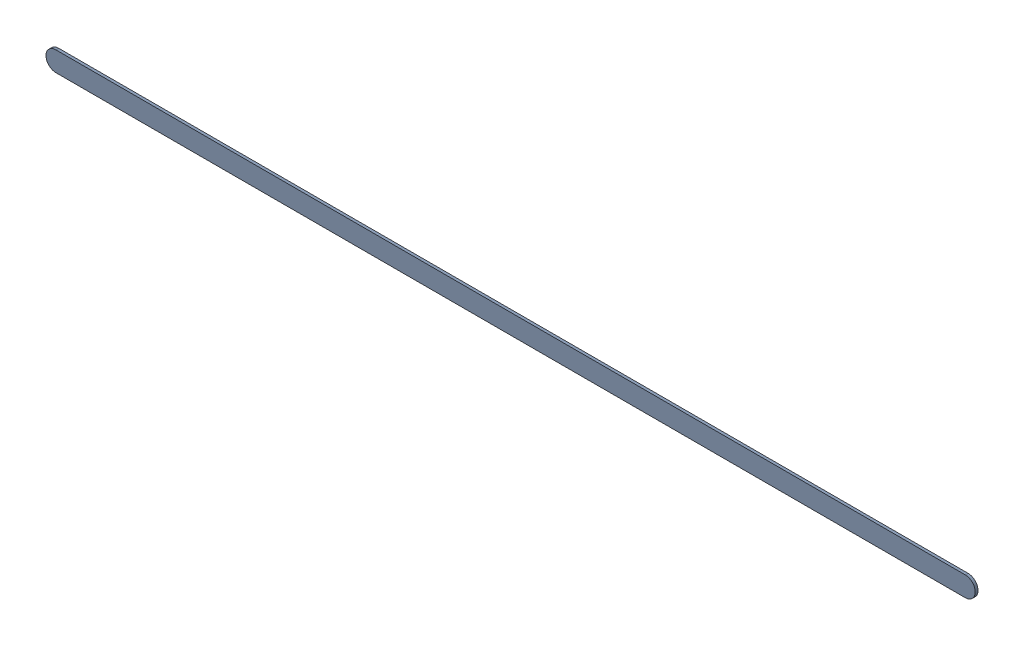
SolidWorks assembly Track (14.5mm,6.8mm)(26.16mm,6.8mm) on Top Layer, configuration Predeterminado. Lengths in mm.
Overall size (11.91 0.25 0.04).
2 component instances, 1 part files, 0 mates.
Components (placement in the parent):
- Track (14.5mm,6.8mm)(26.16mm,6.8mm) on Top Layer-1-1: Track (14.5mm,6.8mm)(26.16mm,6.8mm) on Top Layer-1 [Predeterminado] at (-68.317 -44.187 -0.0457) size (11.91 0.25 0.04)
  - Track (14.5mm,6.8mm)(26.16mm,6.8mm) on Top Layer-Part-1-1: Track (14.5mm,6.8mm)(26.16mm,6.8mm) on Top Layer-Part-1 [Predeterminado] at origin size (11.91 0.25 0.04)
